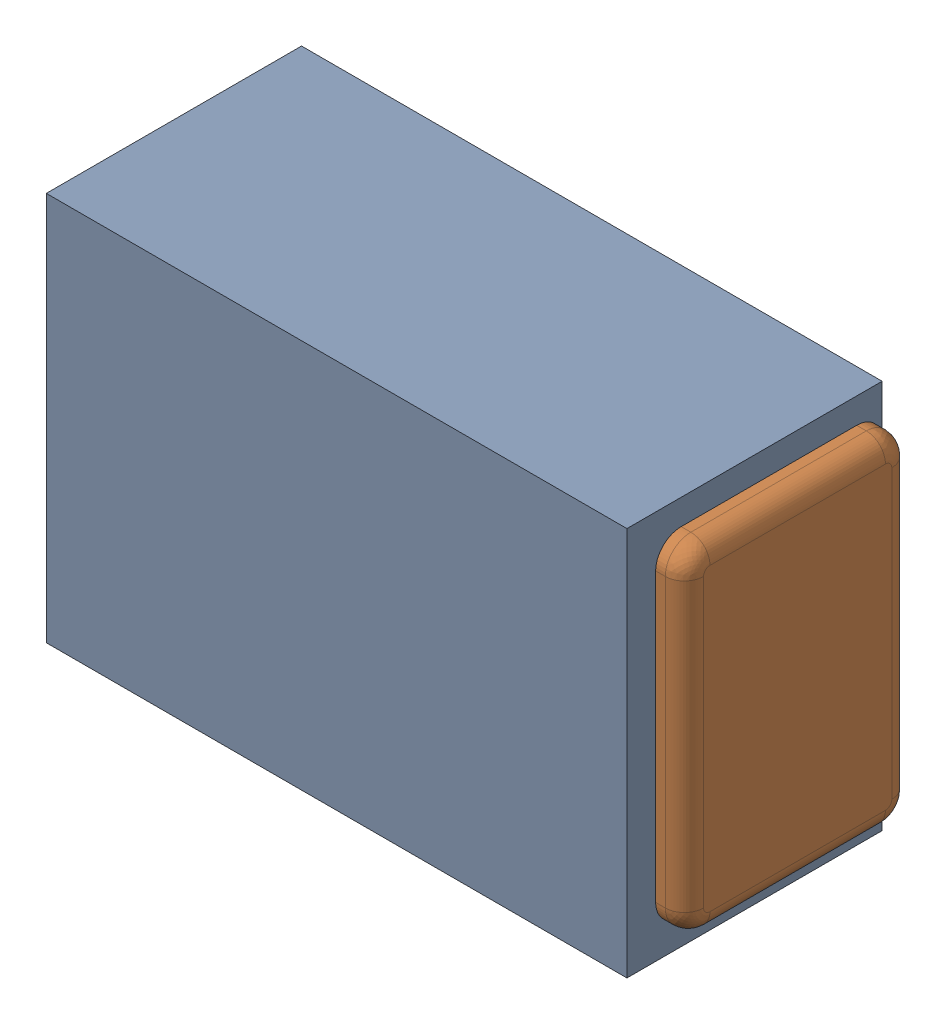
SolidWorks assembly C19, configuration Default. Lengths in mm.
Overall size (1 0.61 0.4).
3 component instances, 2 part files, 0 mates.
Components (placement in the parent):
- 1088880352-1: 1088880352 [Default] at (5.075 9.475 0) size (0.91 0.61 0.4)
  - Extruded-28-1: Extruded-28 [Default] at origin size (0.91 0.61 0.4)
- C0402-1: C0402 [Default] at (5.0751 9.4751 0) x (1 0 0) z (0 -1 0) size (1 0.36 0.54)
